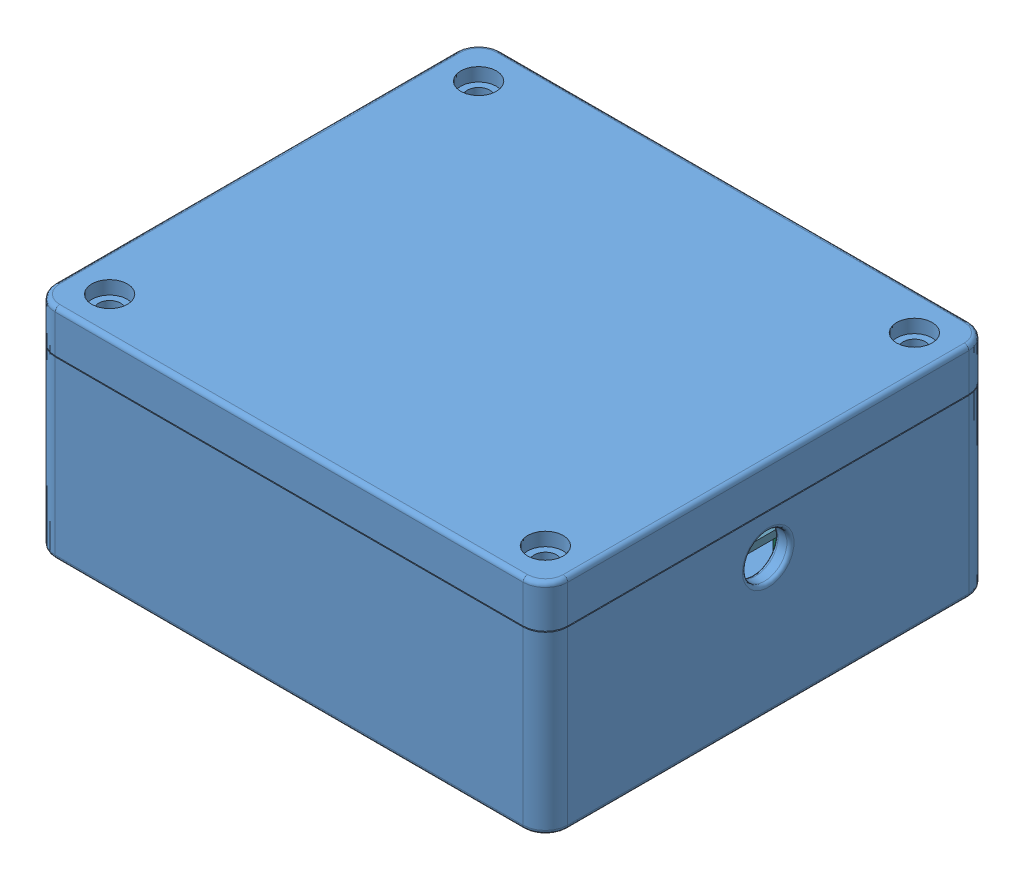
SolidWorks assembly caja_ensamblada, configuration Predeterminado. Lengths in mm.
Overall size (115 57 100).
242 component instances, 213 part files, 12 mates.
Components (placement in the parent):
- caja-1: caja [Predeterminado] at origin size (115 49.2 100)
- mechanism-pcb.STEP-1: mechanism-pcb.STEP [Predeterminado] at (1 17.803 11.5) x (0 0 -1) z (0 1 0) size (66 82 35.01)
  - U1.STEP-1: U1.STEP [Predeterminado] at (-1.8292 0.8108 0.803) x (-1 0 0) z (0 0 1) size (27.9 48.75 13.35)
    - Open CASCADE STEP translator 6.8 1.2.1.STEP-1: Open CASCADE STEP translator 6.8 1.2.1.STEP [Predeterminado] at origin size (27.9 48.75 13.35)
      - Body_1.STEP-1: Body_1.STEP [Predeterminado] x (1 0 0) z (0 -1 0) size (27.9 13.35 48.75)
        - =_[0_1_1_3].STEP-1: =_[0_1_1_3].STEP [Predeterminado] at origin size (0.64 10.63 0.64)
        - =_[0_1_1_4].STEP-1: =_[0_1_1_4].STEP [Predeterminado] at origin size (3.05 0.25 4.06)
        - =_[0_1_1_5].STEP-1: =_[0_1_1_5].STEP [Predeterminado] at origin size (0.64 10.63 0.64)
        - =_[0_1_1_6].STEP-1: =_[0_1_1_6].STEP [Predeterminado] at origin size (2.2 0.75 2.2)
        - =_[0_1_1_7].STEP-1: =_[0_1_1_7].STEP [Predeterminado] at origin size (2 0.4 0.95)
        - =_[0_1_1_8].STEP-1: =_[0_1_1_8].STEP [Predeterminado] at origin size (0.24 0.15 0.82)
        - =_[0_1_1_9].STEP-1: =_[0_1_1_9].STEP [Predeterminado] at origin size (0.5 0.3 1.02)
        - =_[0_1_1_10].STEP-1: =_[0_1_1_10].STEP [Predeterminado] at origin size (0.5 0.3 1.02)
        - =_[0_1_1_11].STEP-1: =_[0_1_1_11].STEP [Predeterminado] at origin size (0.64 10.63 0.64)
        - =_[0_1_1_12].STEP-1: =_[0_1_1_12].STEP [Predeterminado] at origin size (6.9 2.08 4.25)
        - =_[0_1_1_13].STEP-1: =_[0_1_1_13].STEP [Predeterminado] at origin size (0.64 10.63 0.64)
        - =_[0_1_1_14].STEP-1: =_[0_1_1_14].STEP [Predeterminado] at origin size (0.64 10.63 0.64)
        - =_[0_1_1_15].STEP-1: =_[0_1_1_15].STEP [Predeterminado] at origin size (0.64 10.63 0.64)
        - =_[0_1_1_16].STEP-1: =_[0_1_1_16].STEP [Predeterminado] at origin size (0.5 0.3 1.02)
        - =_[0_1_1_17].STEP-1: =_[0_1_1_17].STEP [Predeterminado] at origin size (1.52 1.7 1.52)
        - =_[0_1_1_18].STEP-1: =_[0_1_1_18].STEP [Predeterminado] at origin size (0.64 10.63 0.64)
        - =_[0_1_1_19].STEP-1: =_[0_1_1_19].STEP [Predeterminado] at origin size (1.52 1.7 1.52)
        - =_[0_1_1_20].STEP-1: =_[0_1_1_20].STEP [Predeterminado] at origin size (0.9 0.25 1)
        - =_[0_1_1_21].STEP-1: =_[0_1_1_21].STEP [Predeterminado] at origin size (0.4 0.02 2.25)
        - =_[0_1_1_22].STEP-1: =_[0_1_1_22].STEP [Predeterminado] at origin size (1.52 1.7 1.52)
        - =_[0_1_1_23].STEP-1: =_[0_1_1_23].STEP [Predeterminado] at origin size (1.52 1.7 1.52)
        - =_[0_1_1_24].STEP-1: =_[0_1_1_24].STEP [Predeterminado] at origin size (1.52 1.7 1.52)
        - =_[0_1_1_25].STEP-1: =_[0_1_1_25].STEP [Predeterminado] at origin size (1.52 1.7 1.52)
        - =_[0_1_1_26].STEP-1: =_[0_1_1_26].STEP [Predeterminado] at origin size (1.52 1.7 1.52)
        - =_[0_1_1_27].STEP-1: =_[0_1_1_27].STEP [Predeterminado] at origin size (0.4 0.02 2.25)
        - =_[0_1_1_28].STEP-1: =_[0_1_1_28].STEP [Predeterminado] at origin size (0.64 10.63 0.64)
        - =_[0_1_1_29].STEP-1: =_[0_1_1_29].STEP [Predeterminado] at origin size (0.64 10.63 0.64)
        - =_[0_1_1_30].STEP-1: =_[0_1_1_30].STEP [Predeterminado] at origin size (1.52 1.7 1.52)
        - =_[0_1_1_31].STEP-1: =_[0_1_1_31].STEP [Predeterminado] at origin size (1.52 1.7 1.52)
        - =_[0_1_1_32].STEP-1: =_[0_1_1_32].STEP [Predeterminado] at origin size (1.52 1.7 1.52)
        - =_[0_1_1_33].STEP-1: =_[0_1_1_33].STEP [Predeterminado] at origin size (0.9 0.25 1)
        - =_[0_1_1_34].STEP-1: =_[0_1_1_34].STEP [Predeterminado] at origin size (0.64 10.63 0.64)
        - =_[0_1_1_35].STEP-1: =_[0_1_1_35].STEP [Predeterminado] at origin size (1.52 1.7 1.52)
        - =_[0_1_1_36].STEP-1: =_[0_1_1_36].STEP [Predeterminado] at origin size (2.5 2.8 48.26)
        - =_[0_1_1_37].STEP-1: =_[0_1_1_37].STEP [Predeterminado] at origin size (0.64 10.63 0.64)
        - =_[0_1_1_38].STEP-1: =_[0_1_1_38].STEP [Predeterminado] at origin size (1.52 1.7 1.52)
        - =_[0_1_1_39].STEP-1: =_[0_1_1_39].STEP [Predeterminado] at origin size (0.15 0.14 0.05)
        - =_[0_1_1_40].STEP-1: =_[0_1_1_40].STEP [Predeterminado] at origin size (1.52 1.7 1.52)
        - =_[0_1_1_41].STEP-1: =_[0_1_1_41].STEP [Predeterminado] at origin size (1.52 1.7 1.52)
        - =_[0_1_1_42].STEP-1: =_[0_1_1_42].STEP [Predeterminado] at origin size (1.52 1.7 1.52)
        - =_[0_1_1_43].STEP-1: =_[0_1_1_43].STEP [Predeterminado] at origin size (1.52 1.7 1.52)
        - =_[0_1_1_44].STEP-1: =_[0_1_1_44].STEP [Predeterminado] at origin size (1.52 1.7 1.52)
        - =_[0_1_1_45].STEP-1: =_[0_1_1_45].STEP [Predeterminado] at origin size (0.64 10.63 0.64)
        - =_[0_1_1_46].STEP-1: =_[0_1_1_46].STEP [Predeterminado] at origin size (0.64 10.63 0.64)
        - =_[0_1_1_47].STEP-1: =_[0_1_1_47].STEP [Predeterminado] at origin size (1.52 1.7 1.52)
        - =_[0_1_1_48].STEP-1: =_[0_1_1_48].STEP [Predeterminado] at origin size (2 0.4 3)
        - =_[0_1_1_49].STEP-1: =_[0_1_1_49].STEP [Predeterminado] at origin size (1.52 1.7 1.52)
        - =_[0_1_1_50].STEP-1: =_[0_1_1_50].STEP [Predeterminado] at origin size (1.52 1.7 1.52)
        - =_[0_1_1_51].STEP-1: =_[0_1_1_51].STEP [Predeterminado] at origin size (0.64 10.63 0.64)
        - =_[0_1_1_52].STEP-1: =_[0_1_1_52].STEP [Predeterminado] at origin size (0.15 0.14 0.05)
        - =_[0_1_1_53].STEP-1: =_[0_1_1_53].STEP [Predeterminado] at origin size (3.05 1.4 4.06)
        - =_[0_1_1_54].STEP-1: =_[0_1_1_54].STEP [Predeterminado] at origin size (3.05 0.25 4.06)
        - =_[0_1_1_55].STEP-1: =_[0_1_1_55].STEP [Predeterminado] at origin size (1.52 1.7 1.52)
        - =_[0_1_1_56].STEP-1: =_[0_1_1_56].STEP [Predeterminado] at origin size (0.15 0.14 0.05)
        - =_[0_1_1_57].STEP-1: =_[0_1_1_57].STEP [Predeterminado] at origin size (0.64 10.63 0.64)
        - =_[0_1_1_58].STEP-1: =_[0_1_1_58].STEP [Predeterminado] at origin size (0.64 10.63 0.64)
        - =_[0_1_1_59].STEP-1: =_[0_1_1_59].STEP [Predeterminado] at origin size (1.52 1.7 1.52)
        - =_[0_1_1_60].STEP-1: =_[0_1_1_60].STEP [Predeterminado] at origin size (1.52 1.7 1.52)
        - =_[0_1_1_61].STEP-1: =_[0_1_1_61].STEP [Predeterminado] at origin size (0.64 10.63 0.64)
        - =_[0_1_1_62].STEP-1: =_[0_1_1_62].STEP [Predeterminado] at origin size (0.15 0.14 0.05)
        - =_[0_1_1_63].STEP-1: =_[0_1_1_63].STEP [Predeterminado] at origin size (1.52 1.7 1.52)
        - =_[0_1_1_64].STEP-1: =_[0_1_1_64].STEP [Predeterminado] at origin size (0.64 10.63 0.64)
        - =_[0_1_1_65].STEP-1: =_[0_1_1_65].STEP [Predeterminado] at origin size (1.52 1.7 1.52)
        - =_[0_1_1_66].STEP-1: =_[0_1_1_66].STEP [Predeterminado] at origin size (0.64 10.63 0.64)
        - =_[0_1_1_67].STEP-1: =_[0_1_1_67].STEP [Predeterminado] at origin size (0.64 10.63 0.64)
        - =_[0_1_1_68].STEP-1: =_[0_1_1_68].STEP [Predeterminado] at origin size (0.5 0.3 1.02)
        - =_[0_1_1_69].STEP-1: =_[0_1_1_69].STEP [Predeterminado] at origin size (1.52 1.7 1.52)
        - =_[0_1_1_70].STEP-1: =_[0_1_1_70].STEP [Predeterminado] at origin size (3.05 1 1.27)
        - =_[0_1_1_71].STEP-1: =_[0_1_1_71].STEP [Predeterminado] at origin size (0.15 0.14 0.05)
        - =_[0_1_1_72].STEP-1: =_[0_1_1_72].STEP [Predeterminado] at origin size (0.64 10.63 0.64)
        - =_[0_1_1_73].STEP-1: =_[0_1_1_73].STEP [Predeterminado] at origin size (1.52 1.7 1.52)
        - =_[0_1_1_74].STEP-1: =_[0_1_1_74].STEP [Predeterminado] at origin size (0.64 10.63 0.64)
        - =_[0_1_1_75].STEP-1: =_[0_1_1_75].STEP [Predeterminado] at origin size (27.9 1.7 48.2)
        - =_[0_1_1_76].STEP-1: =_[0_1_1_76].STEP [Predeterminado] at origin size (0.64 10.63 0.64)
        - =_[0_1_1_77].STEP-1: =_[0_1_1_77].STEP [Predeterminado] at origin size (0.24 0.15 0.82)
        - =_[0_1_1_78].STEP-1: =_[0_1_1_78].STEP [Predeterminado] at origin size (0.24 0.15 0.82)
        - =_[0_1_1_79].STEP-1: =_[0_1_1_79].STEP [Predeterminado] at origin size (4 2 6.6)
        - =_[0_1_1_80].STEP-1: =_[0_1_1_80].STEP [Predeterminado] at origin size (1.52 1.7 1.52)
        - =_[0_1_1_81].STEP-1: =_[0_1_1_81].STEP [Predeterminado] at origin size (1.52 1.7 1.52)
        - =_[0_1_1_82].STEP-1: =_[0_1_1_82].STEP [Predeterminado] at origin size (1.52 1.7 1.52)
        - =_[0_1_1_83].STEP-1: =_[0_1_1_83].STEP [Predeterminado] at origin size (1.52 1.7 1.52)
        - =_[0_1_1_84].STEP-1: =_[0_1_1_84].STEP [Predeterminado] at origin size (1.52 1.7 1.52)
        - =_[0_1_1_85].STEP-1: =_[0_1_1_85].STEP [Predeterminado] at origin size (0.64 10.63 0.64)
        - =_[0_1_1_86].STEP-1: =_[0_1_1_86].STEP [Predeterminado] at origin size (1.52 1.7 1.52)
        - =_[0_1_1_87].STEP-1: =_[0_1_1_87].STEP [Predeterminado] at origin size (2.5 2.8 48.26)
        - =_[0_1_1_88].STEP-1: =_[0_1_1_88].STEP [Predeterminado] at origin size (0.24 0.15 0.82)
        - =_[0_1_1_89].STEP-1: =_[0_1_1_89].STEP [Predeterminado] at origin size (0.64 10.63 0.64)
        - =_[0_1_1_90].STEP-1: =_[0_1_1_90].STEP [Predeterminado] at origin size (0.64 10.63 0.64)
        - =_[0_1_1_91].STEP-1: =_[0_1_1_91].STEP [Predeterminado] at origin size (0.4 0.02 2.25)
        - =_[0_1_1_92].STEP-1: =_[0_1_1_92].STEP [Predeterminado] at origin size (3.05 1.4 4.06)
        - =_[0_1_1_93].STEP-1: =_[0_1_1_93].STEP [Predeterminado] at origin size (0.4 0.02 2.25)
        - =_[0_1_1_94].STEP-1: =_[0_1_1_94].STEP [Predeterminado] at origin size (0.9 0.25 1)
        - =_[0_1_1_95].STEP-1: =_[0_1_1_95].STEP [Predeterminado] at origin size (0.5 0.3 1.02)
        - =_[0_1_1_96].STEP-1: =_[0_1_1_96].STEP [Predeterminado] at origin size (0.5 0.3 1.02)
        - =_[0_1_1_97].STEP-1: =_[0_1_1_97].STEP [Predeterminado] at origin size (1.52 1.7 1.52)
        - =_[0_1_1_98].STEP-1: =_[0_1_1_98].STEP [Predeterminado] at origin size (0.64 10.63 0.64)
        - =_[0_1_1_99].STEP-1: =_[0_1_1_99].STEP [Predeterminado] at origin size (1.52 1.7 1.52)
        - =_[0_1_1_100].STEP-1: =_[0_1_1_100].STEP [Predeterminado] at origin size (7.9 2.97 5.57)
        - =_[0_1_1_101].STEP-1: =_[0_1_1_101].STEP [Predeterminado] at origin size (0.64 10.63 0.64)
        - =_[0_1_1_102].STEP-1: =_[0_1_1_102].STEP [Predeterminado] at origin size (0.4 0.02 2.25)
        - =_[0_1_1_103].STEP-1: =_[0_1_1_103].STEP [Predeterminado] at origin size (1.52 1.7 1.52)
        - =_[0_1_1_104].STEP-1: =_[0_1_1_104].STEP [Predeterminado] at origin size (0.64 10.63 0.64)
        - =_[0_1_1_105].STEP-1: =_[0_1_1_105].STEP [Predeterminado] at origin size (2 0.4 0.95)
        - =_[0_1_1_106].STEP-1: =_[0_1_1_106].STEP [Predeterminado] at origin size (1.52 1.7 1.52)
        - =_[0_1_1_107].STEP-1: =_[0_1_1_107].STEP [Predeterminado] at origin size (0.64 10.63 0.64)
        - =_[0_1_1_108].STEP-1: =_[0_1_1_108].STEP [Predeterminado] at origin size (0.24 0.15 0.82)
        - =_[0_1_1_109].STEP-1: =_[0_1_1_109].STEP [Predeterminado] at origin size (0.64 10.63 0.64)
        - =_[0_1_1_110].STEP-1: =_[0_1_1_110].STEP [Predeterminado] at origin size (0.64 10.63 0.64)
        - =_[0_1_1_111].STEP-1: =_[0_1_1_111].STEP [Predeterminado] at origin size (2.2 0.75 2.2)
        - =_[0_1_1_112].STEP-1: =_[0_1_1_112].STEP [Predeterminado] at origin size (0.64 10.63 0.64)
        - =_[0_1_1_113].STEP-1: =_[0_1_1_113].STEP [Predeterminado] at origin size (0.64 10.63 0.64)
        - =_[0_1_1_114].STEP-1: =_[0_1_1_114].STEP [Predeterminado] at origin size (5 1.5 5)
        - =_[0_1_1_115].STEP-1: =_[0_1_1_115].STEP [Predeterminado] at origin size (2 0.4 0.95)
        - =_[0_1_1_116].STEP-1: =_[0_1_1_116].STEP [Predeterminado] at origin size (1.52 1.7 1.52)
        - =_[0_1_1_117].STEP-1: =_[0_1_1_117].STEP [Predeterminado] at origin size (0.9 0.25 1)
        - =_[0_1_1_118].STEP-1: =_[0_1_1_118].STEP [Predeterminado] at origin size (0.64 10.63 0.64)
        - =_[0_1_1_119].STEP-1: =_[0_1_1_119].STEP [Predeterminado] at origin size (0.64 10.63 0.64)
        - =_[0_1_1_120].STEP-1: =_[0_1_1_120].STEP [Predeterminado] at origin size (0.64 10.63 0.64)
        - =_[0_1_1_121].STEP-1: =_[0_1_1_121].STEP [Predeterminado] at origin size (3.05 1 1.27)
        - =_[0_1_1_122].STEP-1: =_[0_1_1_122].STEP [Predeterminado] at origin size (0.64 10.63 0.64)
        - =_[0_1_1_123].STEP-1: =_[0_1_1_123].STEP [Predeterminado] at origin size (0.85 0.8 0.9)
        - =_[0_1_1_124].STEP-1: =_[0_1_1_124].STEP [Predeterminado] at origin size (0.9 0.8 0.85)
        - =_[0_1_1_125].STEP-1: =_[0_1_1_125].STEP [Predeterminado] at origin size (0.9 0.8 0.85)
        - =_[0_1_1_126].STEP-1: =_[0_1_1_126].STEP [Predeterminado] at origin size (0.85 0.8 0.9)
        - =_[0_1_1_127].STEP-1: =_[0_1_1_127].STEP [Predeterminado] at origin size (0.85 0.8 0.9)
        - =_[0_1_1_128].STEP-1: =_[0_1_1_128].STEP [Predeterminado] at origin size (3.6 0.3 3.6)
        - =_[0_1_1_129].STEP-1: =_[0_1_1_129].STEP [Predeterminado] at origin size (0.85 0.8 0.9)
        - =_[0_1_1_130].STEP-1: =_[0_1_1_130].STEP [Predeterminado] at origin size (0.85 0.8 0.9)
        - =_[0_1_1_131].STEP-1: =_[0_1_1_131].STEP [Predeterminado] at origin size (0.85 0.8 0.9)
        - =_[0_1_1_132].STEP-1: =_[0_1_1_132].STEP [Predeterminado] at origin size (0.85 0.8 0.9)
        - =_[0_1_1_133].STEP-1: =_[0_1_1_133].STEP [Predeterminado] at origin size (0.2 0.16 1.8)
        - =_[0_1_1_134].STEP-1: =_[0_1_1_134].STEP [Predeterminado] at origin size (2 1.06 2.55)
        - =_[0_1_1_135].STEP-1: =_[0_1_1_135].STEP [Predeterminado] at origin size (0.85 0.8 0.9)
        - =_[0_1_1_136].STEP-1: =_[0_1_1_136].STEP [Predeterminado] at origin size (0.85 0.8 0.9)
        - =_[0_1_1_137].STEP-1: =_[0_1_1_137].STEP [Predeterminado] at origin size (0.85 0.8 0.9)
        - =_[0_1_1_138].STEP-1: =_[0_1_1_138].STEP [Predeterminado] at origin size (15.65 2.55 17.5)
        - =_[0_1_1_139].STEP-1: =_[0_1_1_139].STEP [Predeterminado] at origin size (0.9 0.8 0.85)
        - =_[0_1_1_140].STEP-1: =_[0_1_1_140].STEP [Predeterminado] at origin size (0.85 0.8 0.9)
        - =_[0_1_1_141].STEP-1: =_[0_1_1_141].STEP [Predeterminado] at origin size (0.85 0.8 0.9)
        - =_[0_1_1_142].STEP-1: =_[0_1_1_142].STEP [Predeterminado] at origin size (0.85 0.8 0.9)
        - =_[0_1_1_143].STEP-1: =_[0_1_1_143].STEP [Predeterminado] at origin size (1.7 0.1 1)
        - =_[0_1_1_144].STEP-1: =_[0_1_1_144].STEP [Predeterminado] at origin size (0.2 0.16 1.8)
        - =_[0_1_1_145].STEP-1: =_[0_1_1_145].STEP [Predeterminado] at origin size (0.85 0.8 0.9)
        - =_[0_1_1_146].STEP-1: =_[0_1_1_146].STEP [Predeterminado] at origin size (0.9 0.8 0.85)
        - =_[0_1_1_147].STEP-1: =_[0_1_1_147].STEP [Predeterminado] at origin size (0.85 0.8 0.9)
        - =_[0_1_1_148].STEP-1: =_[0_1_1_148].STEP [Predeterminado] at origin size (0.9 0.8 0.85)
        - =_[0_1_1_149].STEP-1: =_[0_1_1_149].STEP [Predeterminado] at origin size (2.6 0.35 2.6)
        - =_[0_1_1_150].STEP-1: =_[0_1_1_150].STEP [Predeterminado] at origin size (0.9 0.8 0.85)
        - =_[0_1_1_151].STEP-1: =_[0_1_1_151].STEP [Predeterminado] at origin size (0.9 0.8 0.85)
        - =_[0_1_1_152].STEP-1: =_[0_1_1_152].STEP [Predeterminado] at origin size (0.85 0.8 0.9)
        - =_[0_1_1_153].STEP-1: =_[0_1_1_153].STEP [Predeterminado] at origin size (0.9 0.8 0.85)
        - =_[0_1_1_154].STEP-1: =_[0_1_1_154].STEP [Predeterminado] at origin size (0.85 0.8 0.9)
        - =_[0_1_1_155].STEP-1: =_[0_1_1_155].STEP [Predeterminado] at origin size (0.9 0.8 0.85)
        - =_[0_1_1_156].STEP-1: =_[0_1_1_156].STEP [Predeterminado] at origin size (0.85 0.8 0.9)
        - =_[0_1_1_157].STEP-1: =_[0_1_1_157].STEP [Predeterminado] at origin size (0.85 0.8 0.9)
        - =_[0_1_1_158].STEP-1: =_[0_1_1_158].STEP [Predeterminado] at origin size (18 0.8 19.2)
        - =_[0_1_1_159].STEP-1: =_[0_1_1_159].STEP [Predeterminado] at origin size (0.85 0.8 0.9)
        - =_[0_1_1_160].STEP-1: =_[0_1_1_160].STEP [Predeterminado] at origin size (0.85 0.8 0.9)
        - =_[0_1_1_161].STEP-1: =_[0_1_1_161].STEP [Predeterminado] at origin size (0.5 1.15 0.5)
        - =_[0_1_1_162].STEP-1: =_[0_1_1_162].STEP [Predeterminado] at origin size (0.85 0.8 0.9)
        - =_[0_1_1_163].STEP-1: =_[0_1_1_163].STEP [Predeterminado] at origin size (0.85 0.8 0.9)
        - =_[0_1_1_164].STEP-1: =_[0_1_1_164].STEP [Predeterminado] at origin size (0.6 0.16 0.25)
        - =_[0_1_1_165].STEP-1: =_[0_1_1_165].STEP [Predeterminado] at origin size (0.85 0.8 0.9)
        - =_[0_1_1_166].STEP-1: =_[0_1_1_166].STEP [Predeterminado] at origin size (0.85 0.8 0.9)
        - =_[0_1_1_167].STEP-1: =_[0_1_1_167].STEP [Predeterminado] at origin size (0.85 0.8 0.9)
        - =_[0_1_1_168].STEP-1: =_[0_1_1_168].STEP [Predeterminado] at origin size (0.9 0.8 0.85)
        - =_[0_1_1_169].STEP-1: =_[0_1_1_169].STEP [Predeterminado] at origin size (0.85 0.8 0.9)
        - =_[0_1_1_170].STEP-1: =_[0_1_1_170].STEP [Predeterminado] at origin size (0.85 0.8 0.9)
  - BT.STEP-1: BT.STEP [Predeterminado] at (21.0592 12.3192 0.803) size (7.8 5.99 8.52)
    - Open CASCADE STEP translator 6.8 1.3.1.STEP-1: Open CASCADE STEP translator 6.8 1.3.1.STEP [Predeterminado] at origin size (7.8 5.99 8.52)
      - Body_1-1.STEP-1: Body_1-1.STEP [Predeterminado] x (1 0 0) z (0 -1 0) size (7.8 8.52 5.99)
        - =_[0_1_1_3]-0.STEP-1: =_[0_1_1_3]-0.STEP [Predeterminado] at origin size (0.9 0.1 0.9)
        - =_[0_1_1_4]-1.STEP-1: =_[0_1_1_4]-1.STEP [Predeterminado] at origin size (5.99 3.31 5.99)
        - =_[0_1_1_5]-2.STEP-1: =_[0_1_1_5]-2.STEP [Predeterminado] at origin size (5.99 0.3 5.99)
        - =_[0_1_1_6]-3.STEP-1: =_[0_1_1_6]-3.STEP [Predeterminado] at origin size (0.91 4.45 0.71)
        - =_[0_1_1_7]-4.STEP-1: =_[0_1_1_7]-4.STEP [Predeterminado] at origin size (3.51 1.4 3.51)
        - =_[0_1_1_8]-5.STEP-1: =_[0_1_1_8]-5.STEP [Predeterminado] at origin size (0.91 4.45 0.71)
        - =_[0_1_1_9]-6.STEP-1: =_[0_1_1_9]-6.STEP [Predeterminado] at origin size (0.9 0.1 0.9)
        - =_[0_1_1_10]-7.STEP-1: =_[0_1_1_10]-7.STEP [Predeterminado] at origin size (0.91 4.45 0.71)
        - =_[0_1_1_11]-8.STEP-1: =_[0_1_1_11]-8.STEP [Predeterminado] at origin size (0.9 0.1 0.9)
        - =_[0_1_1_12]-9.STEP-1: =_[0_1_1_12]-9.STEP [Predeterminado] at origin size (0.9 0.1 0.9)
        - =_[0_1_1_13]-10.STEP-1: =_[0_1_1_13]-10.STEP [Predeterminado] at origin size (0.91 4.45 0.71)
  - J1.STEP-1: J1.STEP [Predeterminado] at (26.0892 22.6008 0.803) x (-1 0 0) z (0 0 1) size (7.4 5.75 10.4)
    - Open CASCADE STEP translator 6.8 1.4.1.STEP-1: Open CASCADE STEP translator 6.8 1.4.1.STEP [Predeterminado] at origin size (7.4 5.75 10.4)
      - Body_1-2.STEP-1: Body_1-2.STEP [Predeterminado] x (1 0 0) z (0 -1 0) size (7.4 10.4 5.75)
        - =_[0_1_1_3]-11.STEP-1: =_[0_1_1_3]-11.STEP [Predeterminado] at origin size (7.4 7 5.75)
        - =_[0_1_1_4]-12.STEP-1: =_[0_1_1_4]-12.STEP [Predeterminado] at origin size (0.81 10.3 0.64)
        - =_[0_1_1_5]-13.STEP-1: =_[0_1_1_5]-13.STEP [Predeterminado] at origin size (0.81 10.3 0.64)
  - J4.STEP-1: J4.STEP [Predeterminado] at (20.8908 33.5108 0.803) size (17.4 5.75 10.4)
    - Open CASCADE STEP translator 6.8 1.5.1.STEP-1: Open CASCADE STEP translator 6.8 1.5.1.STEP [Predeterminado] at origin size (17.4 5.75 10.4)
      - Body_1-3.STEP-1: Body_1-3.STEP [Predeterminado] x (1 0 0) z (0 -1 0) size (17.4 10.4 5.75)
        - =_[0_1_1_3]-14.STEP-1: =_[0_1_1_3]-14.STEP [Predeterminado] at origin size (17.4 7 5.75)
        - =_[0_1_1_4]-15.STEP-1: =_[0_1_1_4]-15.STEP [Predeterminado] at origin size (0.64 10.2 0.96)
        - =_[0_1_1_5]-16.STEP-1: =_[0_1_1_5]-16.STEP [Predeterminado] at origin size (0.64 10.2 0.96)
        - =_[0_1_1_6]-17.STEP-1: =_[0_1_1_6]-17.STEP [Predeterminado] at origin size (0.64 10.2 0.64)
        - =_[0_1_1_7]-18.STEP-1: =_[0_1_1_7]-18.STEP [Predeterminado] at origin size (0.64 10.2 0.64)
        - =_[0_1_1_8]-19.STEP-1: =_[0_1_1_8]-19.STEP [Predeterminado] at origin size (0.64 10.2 0.64)
        - =_[0_1_1_9]-20.STEP-1: =_[0_1_1_9]-20.STEP [Predeterminado] at origin size (0.64 10.2 0.64)
  - J3.STEP-1: J3.STEP [Predeterminado] at (-0.3292 -29.9792 0.803) size (12.4 5.75 10.4)
    - Open CASCADE STEP translator 6.8 1.6.1.STEP-1: Open CASCADE STEP translator 6.8 1.6.1.STEP [Predeterminado] at origin size (12.4 5.75 10.4)
      - Body_1-4.STEP-1: Body_1-4.STEP [Predeterminado] x (1 0 0) z (0 -1 0) size (12.4 10.4 5.75)
        - =_[0_1_1_3]-21.STEP-1: =_[0_1_1_3]-21.STEP [Predeterminado] at origin size (12.4 7 5.75)
        - =_[0_1_1_4]-22.STEP-1: =_[0_1_1_4]-22.STEP [Predeterminado] at origin size (0.64 10.2 0.96)
        - =_[0_1_1_5]-23.STEP-1: =_[0_1_1_5]-23.STEP [Predeterminado] at origin size (0.64 10.2 0.96)
        - =_[0_1_1_6]-24.STEP-1: =_[0_1_1_6]-24.STEP [Predeterminado] at origin size (0.64 10.2 0.64)
        - =_[0_1_1_7]-25.STEP-1: =_[0_1_1_7]-25.STEP [Predeterminado] at origin size (0.64 10.2 0.64)
  - J2.STEP-1: J2.STEP [Predeterminado] at (27.0908 -29.6892 0.803) size (9.9 5.75 10.4)
    - Open CASCADE STEP translator 6.8 1.7.1.STEP-1: Open CASCADE STEP translator 6.8 1.7.1.STEP [Predeterminado] at origin size (9.9 5.75 10.4)
      - Body_1-5.STEP-1: Body_1-5.STEP [Predeterminado] x (1 0 0) z (0 -1 0) size (9.9 10.4 5.75)
        - =_[0_1_1_3]-26.STEP-1: =_[0_1_1_3]-26.STEP [Predeterminado] at origin size (9.9 7 5.75)
        - =_[0_1_1_4]-27.STEP-1: =_[0_1_1_4]-27.STEP [Predeterminado] at origin size (0.64 10.2 0.96)
        - =_[0_1_1_5]-28.STEP-1: =_[0_1_1_5]-28.STEP [Predeterminado] at origin size (0.64 10.2 0.96)
        - =_[0_1_1_6]-29.STEP-1: =_[0_1_1_6]-29.STEP [Predeterminado] at origin size (0.64 10.2 0.64)
  - J5.STEP-1: J5.STEP [Predeterminado] at (20 -18 0.803) size (4 17 8.33)
    - Open CASCADE STEP translator 6.8 1.8.1.STEP-1: Open CASCADE STEP translator 6.8 1.8.1.STEP [Predeterminado] at origin size (4 17 8.33)
      - Body_1-30.STEP-1: Body_1-30.STEP [Predeterminado] at origin size (4 17 3)
      - Pin_1.STEP-1: Pin_1.STEP [Predeterminado] x (0 -1 0) z (0 0 1) size (0.66 0.66 7.16)
      - Pin_2.STEP-1: Pin_2.STEP [Predeterminado] at (-2.5 2.5 0) x (0 -1 0) z (0 0 1) size (0.66 0.66 7.16)
      - Pin_3.STEP-1: Pin_3.STEP [Predeterminado] at (-5 5 0) x (0 -1 0) z (0 0 1) size (0.66 0.66 7.16)
      - Pin_4.STEP-1: Pin_4.STEP [Predeterminado] at (-7.5 7.5 0) x (0 -1 0) z (0 0 1) size (0.66 0.66 7.16)
      - Pin_5.STEP-1: Pin_5.STEP [Predeterminado] at (-10 10 0) x (0 -1 0) z (0 0 1) size (0.66 0.66 7.16)
      - Pin_6.STEP-1: Pin_6.STEP [Predeterminado] at (2.5 -2.5 0) x (0 -1 0) z (0 0 1) size (0.66 0.66 7.16)
  - D1.STEP-1: D1.STEP [Predeterminado] at (26.5 2.5 0.803) x (0 1 0) z (0 0 1) size (5.55 5.88 35.01)
    - Open CASCADE STEP translator 6.8 1.9.1.STEP-1: Open CASCADE STEP translator 6.8 1.9.1.STEP [Predeterminado] at origin size (5.55 5.88 35.01)
      - Body_1-6.STEP-1: Body_1-6.STEP [Predeterminado] at origin size (5.55 5.88 35.01)
        - SHELL.STEP-1: SHELL.STEP [Predeterminado] at origin size (5.49 5.88 32.51)
        - =_[0_1_1_4]-31.STEP-1: =_[0_1_1_4]-31.STEP [Predeterminado] at origin size (5.5 5 5)
  - R1.STEP-1: R1.STEP [Predeterminado] at (31.5 17.5 0.803) x (0 -1 0) z (0 0 1) size (10.82 1.37 5.33)
    - Open CASCADE STEP translator 6.8 1.10.1.STEP-1: Open CASCADE STEP translator 6.8 1.10.1.STEP [Predeterminado] at origin size (10.82 1.37 5.33)
      - Body_1-32.STEP-1: Body_1-32.STEP [Predeterminado] at origin size (5.08 1.37 1.37)
      - Pin_1-33.STEP-1: Pin_1-33.STEP [Predeterminado] at origin size (3.2 0.66 4.98)
      - Pin_2-34.STEP-1: Pin_2-34.STEP [Predeterminado] at (20.32 0 0) x (-1 0 0) z (0 0 1) size (3.2 0.66 4.98)
  - Layer_1.STEP-1: Layer_1.STEP [Predeterminado] at origin size (66 82 1.61)
- M3_F_TO_F_15MM_STANDOFF.step-1: M3_F_TO_F_15MM_STANDOFF.step [Predeterminado] at (35 9.5 -27.5) x (1 0 0) z (0 -1 0) size (5.78 5.78 15)
- M3_F_TO_F_15MM_STANDOFF.step-2: M3_F_TO_F_15MM_STANDOFF.step [Predeterminado] at (35 9.5 27.5) x (1 0 0) z (0 -1 0) size (5.78 5.78 15)
- M3_F_TO_F_15MM_STANDOFF.step-3: M3_F_TO_F_15MM_STANDOFF.step [Predeterminado] at (-35 9.5 27.5) x (1 0 0) z (0 -1 0) size (5.78 5.78 15)
- M3_F_TO_F_15MM_STANDOFF.step-4: M3_F_TO_F_15MM_STANDOFF.step [Predeterminado] at (-35 9.5 -27.5) x (1 0 0) z (0 -1 0) size (5.78 5.78 15)
Mates (geometry in assembly coordinates):
- Coincidente1: coordinate: point of caja-1
- Concéntrica1: concentric aligned: cylinder of mechanism-pcb.STEP-1/Layer_1.STEP-1 through (-35 17 27.5) axis (0 -1 0) radius 1.5; cylinder of M3_F_TO_F_15MM_STANDOFF.step-3 through (-35 2 27.5) axis (0 -1 0) radius 1.25
- Concéntrica2: concentric aligned: cylinder of mechanism-pcb.STEP-1/Layer_1.STEP-1 through (35 17 27.5) axis (0 -1 0) radius 1.5; cylinder of M3_F_TO_F_15MM_STANDOFF.step-2 through (35 2 27.5) axis (0 -1 0) radius 1.25
- Concéntrica3: concentric aligned: cylinder of mechanism-pcb.STEP-1/Layer_1.STEP-1 through (35 17 -27.5) axis (0 -1 0) radius 1.5; cylinder of M3_F_TO_F_15MM_STANDOFF.step-1 through (35 2 -27.5) axis (0 -1 0) radius 1.25
- Concéntrica4: concentric aligned: cylinder of mechanism-pcb.STEP-1/Layer_1.STEP-1 through (-35 17 -27.5) axis (0 -1 0) radius 1.5; cylinder of M3_F_TO_F_15MM_STANDOFF.step-4 through (-35 2 -27.5) axis (0 -1 0) radius 1.25
- Coincidente2: coincident anti-aligned: plane of mechanism-pcb.STEP-1/Layer_1.STEP-1 through (-41 17 -33.5) normal (0 -1 0); plane of M3_F_TO_F_15MM_STANDOFF.step-3 through (-35 17 27.5) normal (0 1 0)
- Coincidente3: coincident anti-aligned: plane of mechanism-pcb.STEP-1/Layer_1.STEP-1 through (-41 17 -33.5) normal (0 -1 0); plane of M3_F_TO_F_15MM_STANDOFF.step-2 through (35 17 27.5) normal (0 1 0)
- Coincidente4: coincident anti-aligned: plane of mechanism-pcb.STEP-1/Layer_1.STEP-1 through (-41 17 -33.5) normal (0 -1 0); plane of M3_F_TO_F_15MM_STANDOFF.step-1 through (35 17 -27.5) normal (0 1 0)
- Coincidente5: coincident anti-aligned: plane of mechanism-pcb.STEP-1/Layer_1.STEP-1 through (-41 17 -33.5) normal (0 -1 0); plane of M3_F_TO_F_15MM_STANDOFF.step-4 through (-35 17 -27.5) normal (0 1 0)
- Coincidente6: coincident anti-aligned: plane of caja-1 through (0 2 0) normal (0 1 0); plane of M3_F_TO_F_15MM_STANDOFF.step-1 through (35 2 -27.5) normal (0 -1 0)
- Concéntrica9: concentric anti-aligned: cylinder of caja-1 through (35 0 -27.5) axis (0 1 0) radius 1.675; cylinder of M3_F_TO_F_15MM_STANDOFF.step-1 through (35 2 -27.5) axis (0 -1 0) radius 1.25
- Concéntrica10: concentric anti-aligned: cylinder of caja-1 through (-35 0 27.5) axis (0 1 0) radius 1.675; cylinder of mechanism-pcb.STEP-1/Layer_1.STEP-1 through (-35 17 27.5) axis (0 -1 0) radius 1.5
